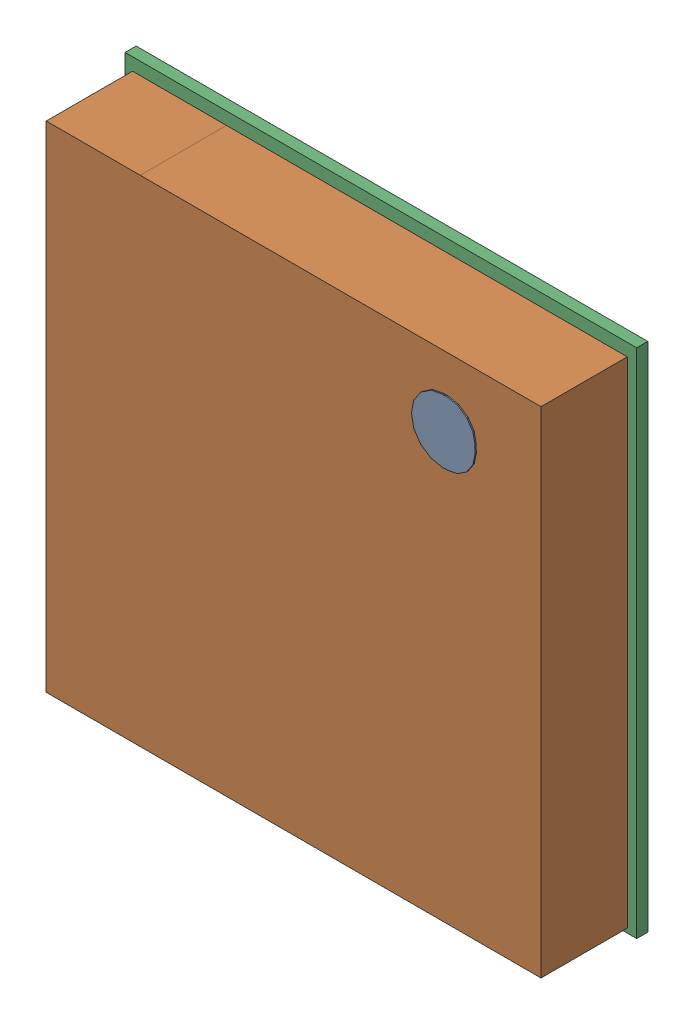
SolidWorks assembly U1, configuration Default. Lengths in mm.
Overall size (4.15 4.15 0.8).
6 component instances, 3 part files, 0 mates.
Components (placement in the parent):
- 577142096-1: 577142096 [Default] at (110.9011 189.8396 0.8) size (0.52 0.52 0.01)
  - Extruded_45-1: Extruded_45 [Default] at origin size (0.52 0.52 0.01)
- 577141584-1: 577141584 [Default] at (109.6772 188.3918 0.1) size (4.01 4.01 0.7)
  - Extruded_46-1: Extruded_46 [Default] at origin size (4.01 4.01 0.7)
- 577142224-1: 577142224 [Default] at (109.685 188.425 0.01) size (4.15 4.15 0.09)
  - Extruded_47-1: Extruded_47 [Default] at origin size (4.15 4.15 0.09)
